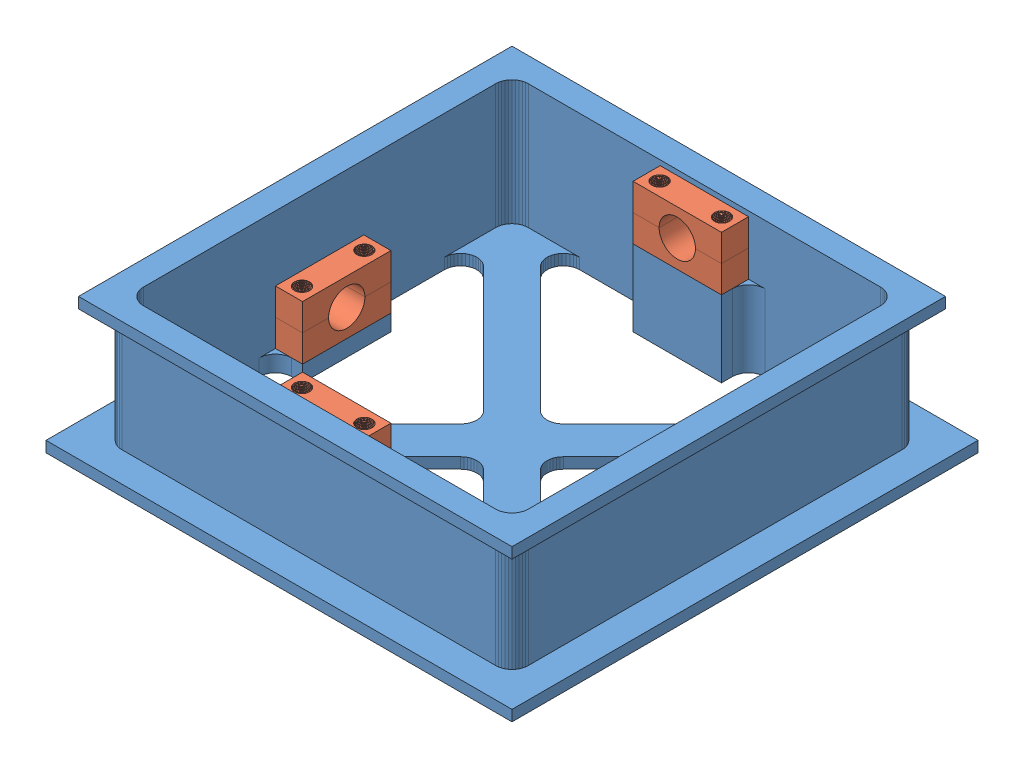
SolidWorks assembly AIR_CORE_ASSEMBLY, configuration Default. Lengths in mm.
Overall size (86 25 86).
9 component instances, 2 part files, 30 mates.
Components (placement in the parent):
- AIR_CORE_FRAME-1: AIR_CORE_FRAME [Default] at (-138.7952 -10.742 4.8277) size (86 25 86)
- ROD_HAT-1: ROD_HAT [Default] at (-94.7952 5.828 13.3277) x (1 0 0) z (0 0 -1) size (16.31 5.11 5)
- ROD_HAT-2: ROD_HAT [Default] at (-94.7952 10.828 18.3277) size (16.31 5.11 5)
- ROD_HAT-3: ROD_HAT [Default] at (-94.7952 5.828 79.3277) x (1 0 0) z (0 0 -1) size (16.31 5.11 5)
- ROD_HAT-4: ROD_HAT [Default] at (-94.7952 10.828 84.3277) size (16.31 5.11 5)
- ROD_HAT-5: ROD_HAT [Default] at (-59.2952 -5.242 48.8277) x (0 0 1) z (1 0 0) size (16.31 5.11 5)
- ROD_HAT-7: ROD_HAT [Default] at (-59.2952 -0.242 48.8277) x (0 0 -1) z (1 0 0) size (16.31 5.11 5)
- ROD_HAT-8: ROD_HAT [Default] at (-125.2952 -5.242 48.8277) x (0 0 1) z (1 0 0) size (16.31 5.11 5)
- ROD_HAT-9: ROD_HAT [Default] at (-125.2952 -0.242 48.8277) x (0 0 -1) z (1 0 0) size (16.31 5.11 5)
Mates (geometry in assembly coordinates):
- Concentric1: concentric anti-aligned: circle of ROD_HAT-1; circle of ROD_HAT-2
- Concentric2: concentric anti-aligned: circle of ROD_HAT-1; circle of ROD_HAT-2
- Concentric3: concentric anti-aligned: circle of ROD_HAT-1; circle of ROD_HAT-2
- Coincident4: coincident anti-aligned: line of ROD_HAT-1 through (-102.9502 8.328 18.3277) axis (0 0 -1); line of ROD_HAT-2 through (-102.9502 8.328 13.3277) axis (0 0 1)
- Coincident5: coincident aligned: line of AIR_CORE_FRAME-1 through (-102.9502 3.328 18.3277) axis (1 0 0); line of ROD_HAT-1 through (-102.9502 3.328 18.3277) axis (1 0 0)
- Coincident6: coincident: point of AIR_CORE_FRAME-1; point of ROD_HAT-1
- Coincident7: coincident anti-aligned: plane of AIR_CORE_FRAME-1 through (-138.7952 -10.742 13.3277) normal (0 0 1); plane of ROD_HAT-1 through (-94.7952 5.828 13.3277) normal (0 0 -1)
- Concentric4: concentric anti-aligned: circle of ROD_HAT-3; circle of ROD_HAT-4
- Concentric5: concentric anti-aligned: circle of ROD_HAT-3; circle of ROD_HAT-4
- Concentric6: concentric anti-aligned: circle of ROD_HAT-3; circle of ROD_HAT-4
- Coincident11: coincident: point of ROD_HAT-3; point of ROD_HAT-4
- Coincident12: coincident aligned: line of AIR_CORE_FRAME-1 through (-102.9502 3.328 79.3277) axis (1 0 0); line of ROD_HAT-3 through (-102.9502 3.328 79.3277) axis (1 0 0)
- Coincident13: coincident: point of AIR_CORE_FRAME-1; point of ROD_HAT-3
- Coincident14: coincident anti-aligned: plane of AIR_CORE_FRAME-1 through (-62.2952 -8.742 84.3277) normal (0 0 -1); plane of ROD_HAT-3 through (-94.7952 5.828 84.3277) normal (0 0 1)
- Concentric7: concentric aligned: circle of ROD_HAT-1; circle of ROD_HAT-3
- Concentric9: concentric aligned: circle of ROD_HAT-5; circle of ROD_HAT-7
- Concentric10: concentric anti-aligned: circle of ROD_HAT-5; circle of ROD_HAT-7
- Concentric11: concentric anti-aligned: circle of ROD_HAT-5; circle of ROD_HAT-7
- Coincident19: coincident: point of ROD_HAT-5; point of ROD_HAT-7
- Coincident20: coincident anti-aligned: line of AIR_CORE_FRAME-1 through (-64.2952 -7.742 56.9827) axis (0 0 -1); line of ROD_HAT-5 through (-64.2952 -7.742 40.6727) axis (0 0 1)
- Coincident21: coincident: point of AIR_CORE_FRAME-1; point of ROD_HAT-5
- Coincident22: coincident anti-aligned: plane of AIR_CORE_FRAME-1 through (-59.2952 -8.742 16.3277) normal (-1 0 0); plane of ROD_HAT-7 through (-59.2952 -0.242 48.8277) normal (1 0 0)
- Concentric12: concentric aligned: circle of ROD_HAT-8; circle of ROD_HAT-9
- Concentric13: concentric anti-aligned: circle of ROD_HAT-8; circle of ROD_HAT-9
- Concentric14: concentric anti-aligned: circle of ROD_HAT-8; circle of ROD_HAT-9
- Coincident26: coincident: point of ROD_HAT-8; point of ROD_HAT-9
- Coincident27: coincident anti-aligned: line of AIR_CORE_FRAME-1 through (-125.2952 -7.742 56.9827) axis (0 0 -1); line of ROD_HAT-8 through (-125.2952 -7.742 40.6727) axis (0 0 1)
- Coincident28: coincident: point of AIR_CORE_FRAME-1; point of ROD_HAT-8
- Coincident29: coincident anti-aligned: plane of AIR_CORE_FRAME-1 through (-130.2952 -8.742 81.3277) normal (1 0 0); plane of ROD_HAT-8 through (-130.2952 -5.242 48.8277) normal (-1 0 0)
- Concentric15: concentric aligned: circle of ROD_HAT-5; circle of ROD_HAT-8
